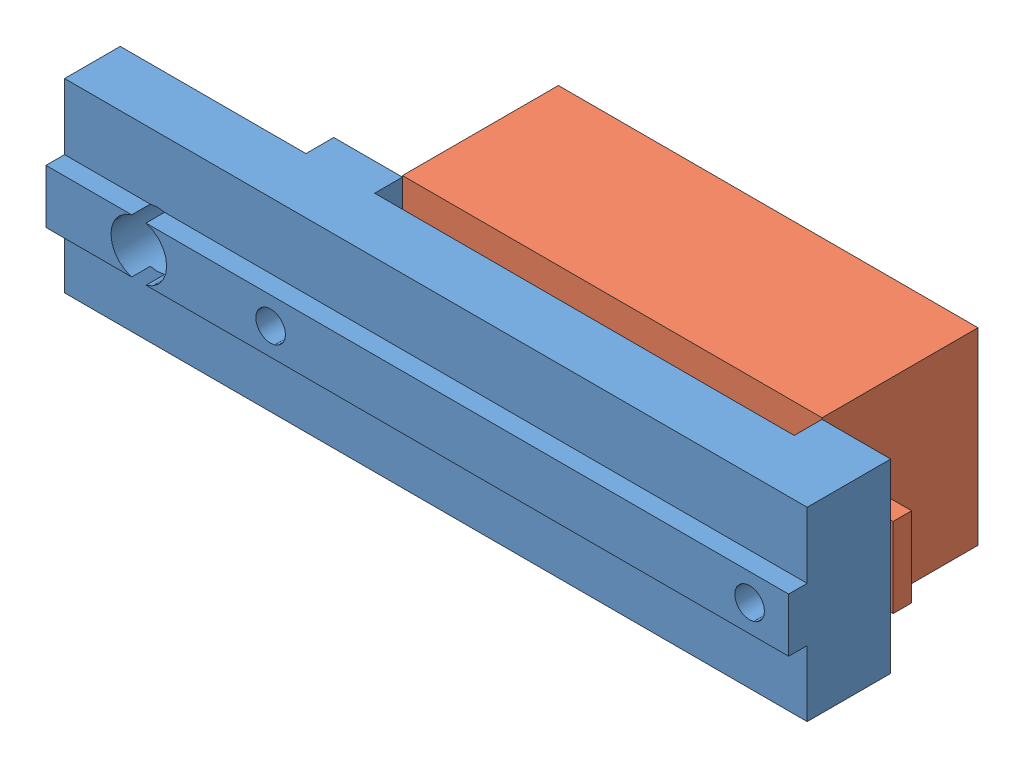
SolidWorks assembly LCD_MiniVoltmeterAndSupportAssembly, configuration Default. Lengths in mm.
Overall size (40.12 10.15 13.9).
2 component instances, 2 part files, 3 mates.
Components (placement in the parent):
- LCD_MiniVoltmeterSupport-1: LCD_MiniVoltmeterSupport [Default] at (-6.7235 18.6655 28.4301) size (40 10 5.5)
- LCD_MiniVoltmeter-1: LCD_MiniVoltmeter [Default] at (18.2765 23.6655 26.9301) x (1 0 0) z (0 0 -1) size (30.25 10.15 8.4)
Mates (geometry in assembly coordinates):
- Concentric1: concentric: cylinder of LCD_MiniVoltmeterSupport-1 through (31.1765 23.6655 32.4301) axis (0 0 -1) radius 0.8; cylinder of LCD_MiniVoltmeter-1 through (31.1765 23.6655 21.3269) axis (0 0 1) radius 1.15
- Concentric2: concentric: cylinder of LCD_MiniVoltmeterSupport-1 through (5.3765 23.6655 32.4301) axis (0 0 -1) radius 0.8; cylinder of LCD_MiniVoltmeter-1 through (5.3765 23.6655 21.3269) axis (0 0 1) radius 1.15
- Coincident1: coincident anti-aligned: plane of LCD_MiniVoltmeterSupport-1 through (-6.7235 18.6655 26.9301) normal (0 0 -1); plane of LCD_MiniVoltmeter-1 through (18.2765 23.6655 26.9301) normal (0 0 1)
